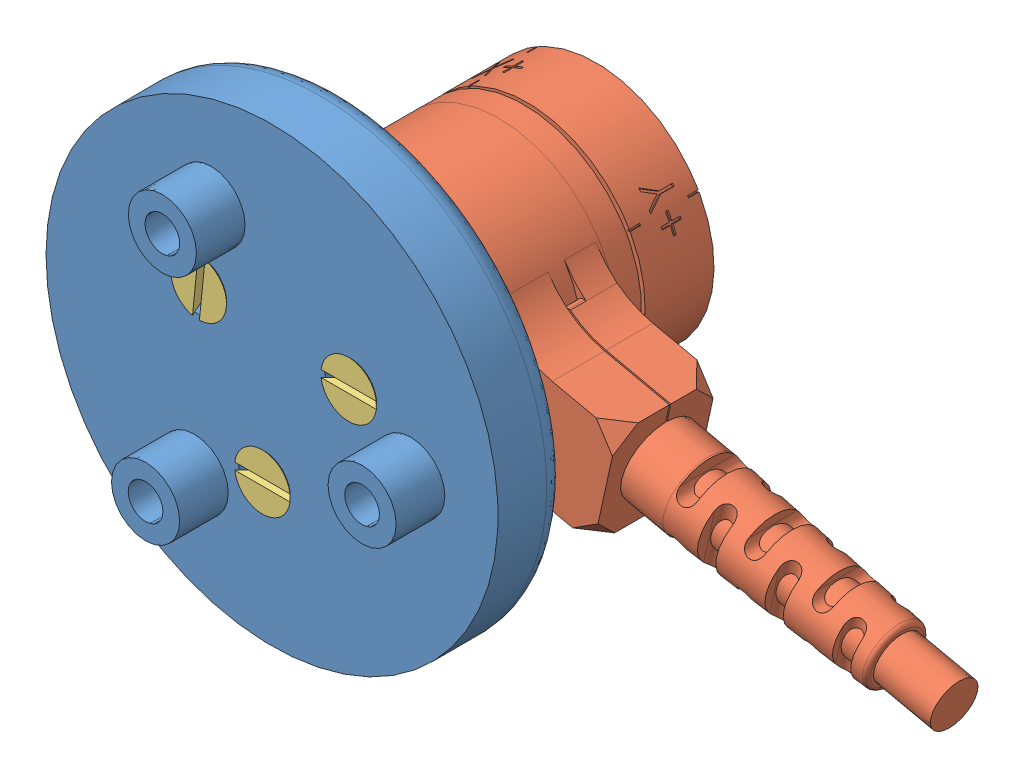
SolidWorks assembly Assem1, configuration Default. Lengths in mm.
Overall size (53.96 41.78 26.74).
5 component instances, 3 part files, 7 mates.
Components (placement in the parent):
- loadCell-1: loadCell [Default] at (9.0822 19.4705 20.6002) size (32.5 32.5 8.5)
- ATI-Default-1: ATI-Default [Default] at (9.1209 19.4653 2.3554) x (0.862886 -0.505399 0) z (0 0 -1) size (44.48 21.66 14.48)
- M2x10 countersunk-1: M2x10 countersunk [Default] at (3.9625 23.0553 24.7502) x (0.099885 0.994999 0) z (0.994999 -0.099885 0) size (3.97 10 4)
- M2x10 countersunk-2: M2x10 countersunk [Default] at (8.5375 13.2442 24.7502) x (1 0 0) z (0 -1 0) size (3.97 10 4)
- M2x10 countersunk-3: M2x10 countersunk [Default] at (14.7466 22.1118 24.7502) x (1 0 0) z (0 -1 0) size (3.97 10 4)
Mates (geometry in assembly coordinates):
- Concentric10: concentric anti-aligned: cylinder of loadCell-1 through (3.9625 23.0553 25.6002) axis (0 0 -1) radius 1; cylinder of M2x10 countersunk-1 through (3.9625 23.0553 24.7502) axis (0 0 1) radius 0.75
- Tangent3: tangent: circle of loadCell-1; cone of M2x10 countersunk-1 through (3.9625 23.0553 24.5002) axis (0 0 -1)
- Concentric11: concentric anti-aligned: cylinder of loadCell-1 through (8.5375 13.2442 25.6002) axis (0 0 -1) radius 1; cylinder of M2x10 countersunk-2 through (8.5375 13.2442 24.7502) axis (0 0 1) radius 0.75
- Tangent4: tangent: circle of loadCell-1; cone of M2x10 countersunk-2 through (8.5375 13.2442 24.5002) axis (0 0 -1)
- Concentric12: concentric anti-aligned: cylinder of loadCell-1 through (14.7466 22.1118 25.6002) axis (0 0 -1) radius 1; cylinder of M2x10 countersunk-3 through (14.7466 22.1118 24.7502) axis (0 0 1) radius 0.75
- Tangent5: tangent: circle of loadCell-1; cone of M2x10 countersunk-3 through (14.7466 22.1118 24.5002) axis (0 0 -1)
- Concentric14: concentric aligned: circle of ATI-Default-1; circle of M2x10 countersunk-2
